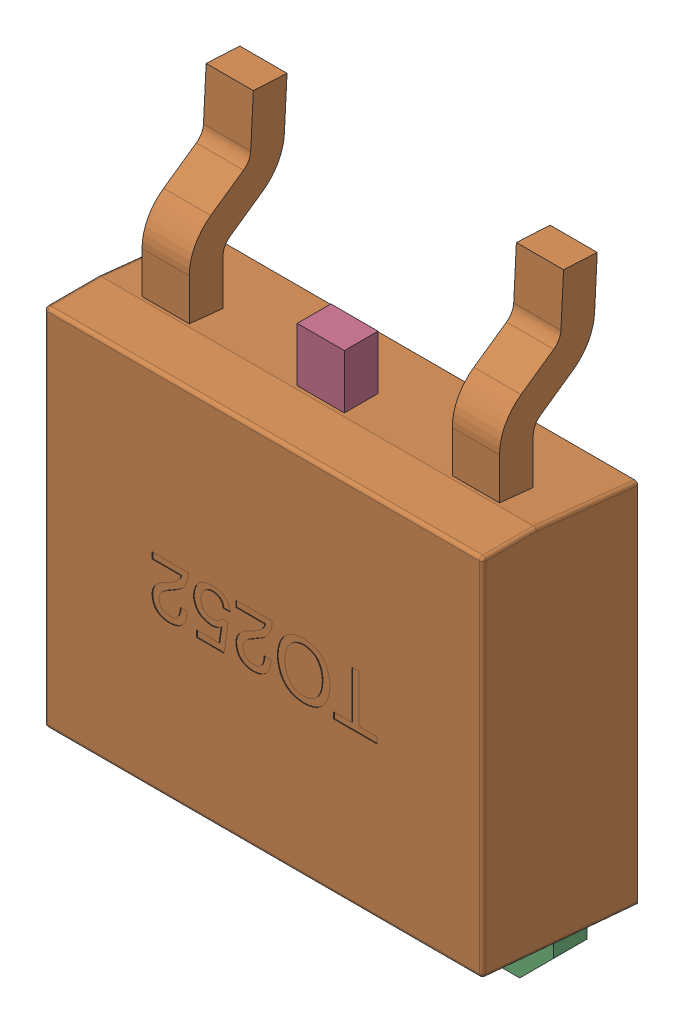
SolidWorks assembly MBG2, configuration 默认. Lengths in mm.
Overall size (6.5 9.42 2.31).
3 component instances, 2 part files, 0 mates.
Components (placement in the parent):
- TO252-1: TO252 [默认] at (60.212 45.7069 0) x (-1 0 0) z (0 0 1) size (6.5 9.42 2.31)
  - LOGO_-1: LOGO_ [默认] at (2.3503 3.4211 -0.0025) x (-1 0 0) z (0 0 -1) size (0.75 0.87 0.01)
  - TO252-1: TO252 [默认] at origin size (6.5 9.42 2.3)
